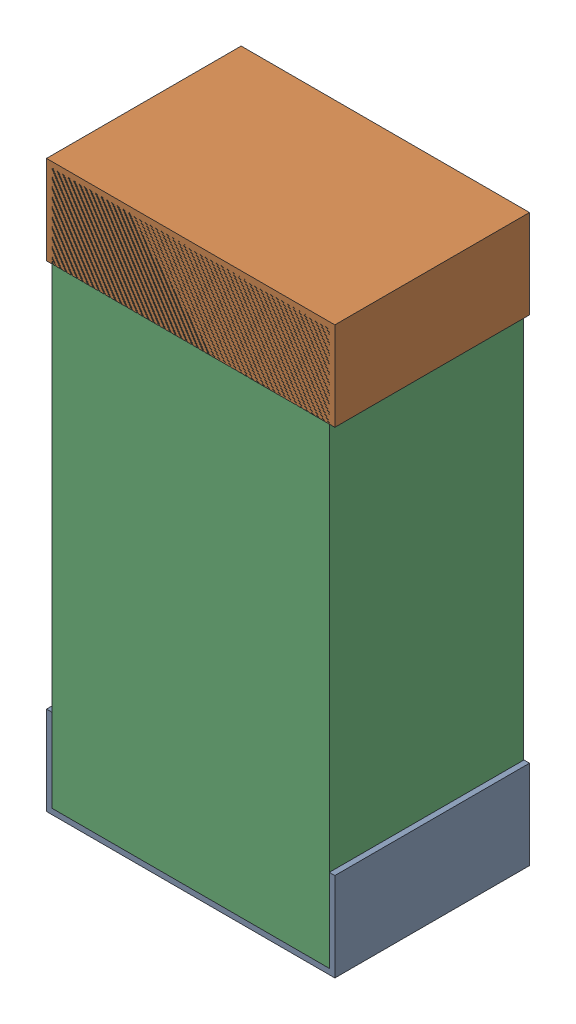
SolidWorks assembly C22, configuration Default. Lengths in mm.
Overall size (0.52 1.02 0.35).
6 component instances, 2 part files, 0 mates.
Components (placement in the parent):
- 870941120-1: 870941120 [Default] at (7.493 41.099 -1.9516) size (0.52 0.16 0.35)
  - Extruded_3-1: Extruded_3 [Default] at origin size (0.52 0.16 0.35)
- 870941120-2: 870941120 [Default] at (7.493 41.959 -1.9516) size (0.52 0.16 0.35)
  - Extruded_3-1: Extruded_3 [Default] at origin size (0.52 0.16 0.35)
- 870941280-1: 870941280 [Default] at (7.493 41.529 -1.9506) size (0.5 1 0.35)
  - Extruded_4-1: Extruded_4 [Default] at origin size (0.5 1 0.35)
